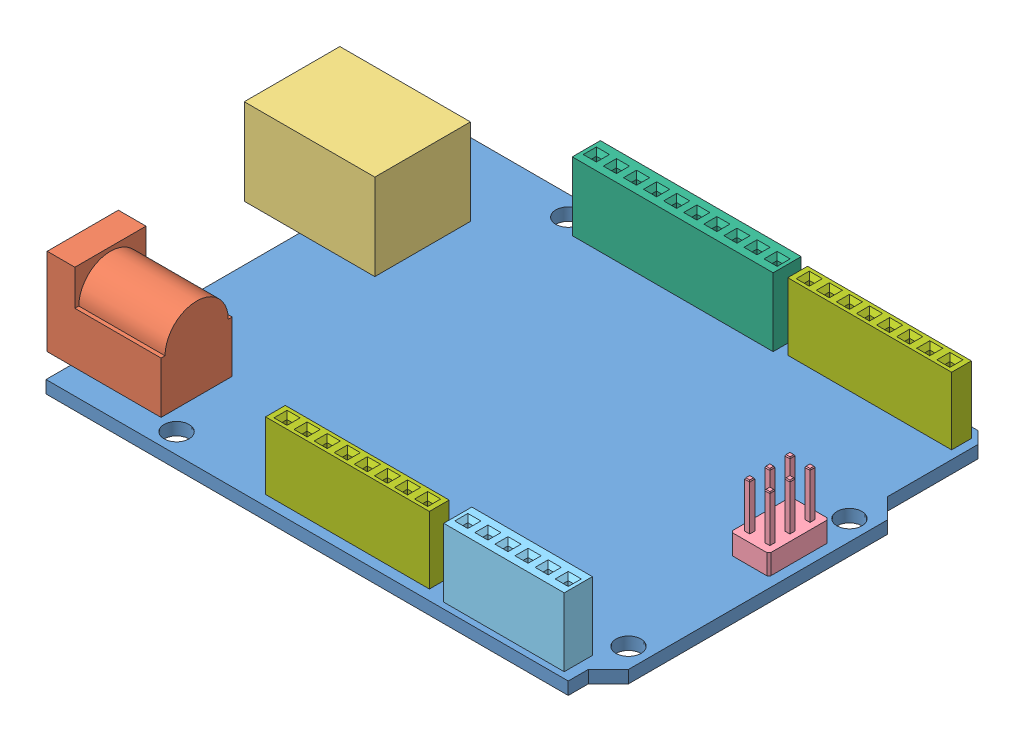
SolidWorks assembly Arduino Uno, configuration Default. Lengths in mm.
Overall size (75.56 12.59 53.34).
8 component instances, 7 part files, 23 mates.
Components (placement in the parent):
- Arduino Uno PCB-1: Arduino Uno PCB [Default] at (2.1062 35.2401 73.447) size (68.58 1.59 53.34)
- PJ-102A-1: PJ-102A [Default] at (-0.8638 36.8276 70.327) x (0 0 -1) z (1 0 0) size (9 11 14.4)
- USB-B1HSW6-1: USB-B1HSW6 [Default] at (11.6312 36.8276 41.3922) x (0 0 -1) z (1 0 0) size (12.09 10.9 16.51)
- 67996-406HLF-1: 67996-406HLF [Default] at (69.4293 36.8276 49.367) x (0 0 -1) z (1 0 0) size (7.62 8.38 4.83)
- 5-534237-4-1: 5-534237-4 [Default] at (51.6362 36.8276 72.685) size (15.24 8.64 3.56)
- 5-534237-8-1: 5-534237-8 [Default] at (19.6322 36.8276 24.425) size (25.4 8.64 3.56)
- M20-7820842-1: M20-7820842 [Default] at (46.3562 36.8276 23.897) size (20.72 8.5 2.5)
- M20-7820842-2: M20-7820842 [Default] at (28.5762 36.8276 72.157) size (20.72 8.5 2.5)
Mates (geometry in assembly coordinates):
- Coincident1: coincident anti-aligned: plane of Arduino Uno PCB-1 through (2.1062 36.8276 73.447) normal (0 1 0); plane of PJ-102A-1 through (2.6362 36.8276 70.272) normal (0 -1 0)
- Distance1: distance = 3.12 mm: line of PJ-102A-1 through (13.5362 36.8276 70.327) axis (-1 0 0); line of Arduino Uno PCB-1 through (2.1062 36.8276 73.447) axis (1 0 0)
- Distance2: distance = 11.43 mm: line of Arduino Uno PCB-1 through (2.1062 36.8276 20.107) axis (0 0 1); line of PJ-102A-1 through (13.5362 36.8276 61.327) axis (0 0 1)
- Coincident4: coincident anti-aligned: plane of Arduino Uno PCB-1 through (2.1062 36.8276 73.447) normal (0 1 0); plane of USB-B1HSW6-1 through (11.6312 36.8276 41.062) normal (0 -1 0)
- Parallel2: parallel aligned: line of Arduino Uno PCB-1 through (2.1062 36.8276 73.447) axis (1 0 0); line of USB-B1HSW6-1 through (-4.8788 36.8276 41.062) axis (1 0 0)
- Distance4: distance = 32.0548 mm: line of USB-B1HSW6-1 through (-4.8788 36.8276 41.3922) axis (1 0 0); line of Arduino Uno PCB-1 through (2.1062 36.8276 73.447) axis (1 0 0)
- Distance5: distance = 9.525 mm: line of Arduino Uno PCB-1 through (2.1062 36.8276 20.107) axis (0 0 1); line of USB-B1HSW6-1 through (11.6312 36.8276 41.3922) axis (0 0 -1)
- Parallel3: parallel: line of Arduino Uno PCB-1 through (70.6862 36.8276 68.367) axis (0 0 -1); line of 67996-406HLF-1 through (69.4293 36.8276 49.113) axis (0 0 -1)
- Coincident12: coincident: plane of Arduino Uno PCB-1 through (2.1062 36.8276 73.447) normal (0 1 0); plane of 67996-406HLF-1 through (69.4293 36.8276 49.367) normal (0 -1 0)
- Distance7: distance = 24.08 mm: plane of 67996-406HLF-1 through (69.4293 39.3676 49.367) normal (0 0 1); line of Arduino Uno PCB-1 through (2.1062 36.8276 73.447) axis (1 0 0)
- Distance8: distance = 63.3225 mm: line of Arduino Uno PCB-1 through (2.1062 36.8276 20.107) axis (0 0 1); plane of 67996-406HLF-1 through (65.4288 45.2096 43.3345) normal (-1 0 0)
- Coincident16: coincident anti-aligned: plane of Arduino Uno PCB-1 through (2.1062 36.8276 73.447) normal (0 1 0); plane of 5-534237-4-1 through (51.6362 36.8276 72.685) normal (0 -1 0)
- Distance9: distance = 0.762 mm: line of 5-534237-4-1 through (51.6362 36.8276 72.685) axis (1 0 0); line of Arduino Uno PCB-1 through (2.1062 36.8276 73.447) axis (1 0 0)
- Distance10: distance = 49.53 mm aligned: plane of Arduino Uno PCB-1 through (2.1062 36.8276 73.447) normal (-1 0 0); plane of 5-534237-4-1 through (51.6362 45.4636 72.685) normal (-1 0 0)
- Coincident18: coincident: plane of Arduino Uno PCB-1 through (2.1062 36.8276 73.447) normal (0 1 0); plane of 5-534237-8-1 through (19.6322 36.8276 24.425) normal (0 -1 0)
- Distance11: distance = 0.762 mm: line of 5-534237-8-1 through (45.0322 36.8276 20.869) axis (-1 0 0); line of Arduino Uno PCB-1 through (66.6222 36.8276 20.107) axis (-1 0 0)
- Distance12: distance = 17.526 mm: plane of 5-534237-8-1 through (19.6322 45.4636 24.425) normal (-1 0 0); line of Arduino Uno PCB-1 through (2.1062 36.8276 20.107) axis (0 0 1)
- Coincident20: coincident: plane of Arduino Uno PCB-1 through (2.1062 36.8276 73.447) normal (0 1 0); plane of M20-7820842-1 through (46.3562 36.8276 23.897) normal (0 -1 0)
- Distance13: distance = 45.4025 mm: plane of M20-7820842-1 through (47.5087 38.9776 22.3295) normal (1 0 0); line of Arduino Uno PCB-1 through (2.1062 36.8276 20.107) axis (0 0 1)
- Distance14: distance = 2.2225 mm anti-aligned: plane of Arduino Uno PCB-1 through (2.1062 36.8276 20.107) normal (0 0 -1); plane of M20-7820842-1 through (47.5087 38.9776 22.3295) normal (0 0 1)
- Coincident23: coincident anti-aligned: plane of Arduino Uno PCB-1 through (2.1062 36.8276 73.447) normal (0 1 0); plane of M20-7820842-2 through (28.5762 36.8276 72.157) normal (0 -1 0)
- Coincident24: coincident aligned: plane of 5-534237-4-1 through (52.5887 39.1136 71.2245) normal (0 0 -1); plane of M20-7820842-2 through (47.5087 38.9776 71.2245) normal (0 0 -1)
- Distance15: distance = 27.6225 mm anti-aligned: plane of M20-7820842-2 through (29.7287 38.9776 70.5895) normal (1 0 0); plane of Arduino Uno PCB-1 through (2.1062 36.8276 73.447) normal (-1 0 0)
